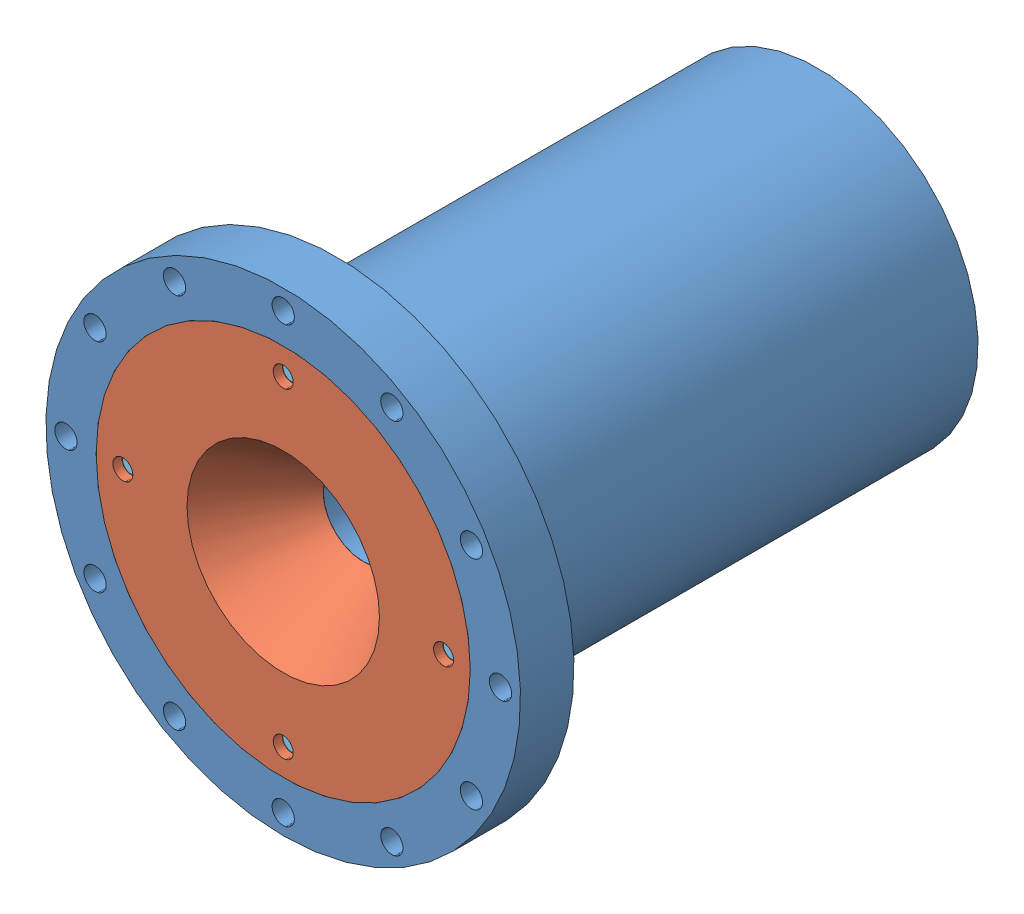
SolidWorks assembly ModularNozzeAssy, configuration Default. Lengths in mm.
Overall size (112.78 112.78 127).
11 component instances, 5 part files, 22 mates.
Components (placement in the parent):
- ModularNozzleBase-1: ModularNozzleBase [Default] at origin size (112.78 112.78 127)
- ConvergingInsert1-1: ConvergingInsert1 [Default] at (0 0 63.5) size (88.9 88.9 19.05)
- DivergingInsert1-1: DivergingInsert1 [Default] at (0 0 38.1) size (63.5 63.5 101.6)
- socket head cap screw_ai-2: socket head cap screw_ai [HX-SHCS 0.19-32x2x1.125-N] at (-22.86 0 44.45) x (0 0 -1) z (0.412891 -0.91078 0) size (55.63 7.94 7.94)
- socket head cap screw_ai-3: socket head cap screw_ai [HX-SHCS 0.19-32x2x1.125-N] at (0 22.86 44.45) x (0 0 -1) z (0.931686 -0.363265 0) size (55.63 7.94 7.94)
- socket head cap screw_ai-4: socket head cap screw_ai [HX-SHCS 0.19-32x2x1.125-N] at (22.86 0 44.45) x (0 0 -1) z (0.730359 0.683064 0) size (55.63 7.94 7.94)
- socket head cap screw_ai-5: socket head cap screw_ai [HX-SHCS 0.19-32x2x1.125-N] at (0 -22.86 44.45) x (0 0 -1) z (0.252159 -0.967686 0) size (55.63 7.94 7.94)
- dowel pin (hardened production)_ai-3: dowel pin (hardened production)_ai [ASME B18.8.2 - 0.1877x0.375] at (0 38.1 61.595) x (0 0 -1) z (0.976041 0.217586 0) size (9.53 4.77 4.77)
- dowel pin (hardened production)_ai-4: dowel pin (hardened production)_ai [ASME B18.8.2 - 0.1877x0.375] at (-38.1 0 61.595) x (0 0 -1) z (1 0 0) size (9.53 4.77 4.77)
- dowel pin (hardened production)_ai-5: dowel pin (hardened production)_ai [ASME B18.8.2 - 0.1877x0.375] at (38.1 0 61.595) x (0 0 -1) z (0.837341 0.546681 0) size (9.53 4.77 4.77)
- dowel pin (hardened production)_ai-6: dowel pin (hardened production)_ai [ASME B18.8.2 - 0.1877x0.375] at (0 -38.1 61.595) x (0 0 -1) z (1 0 0) size (9.53 4.77 4.77)
Mates (geometry in assembly coordinates):
- Concentric1: concentric: cylinder of ModularNozzleBase-1 through (0 0 58.42) axis (0 0 1) radius 44.45; cylinder of ConvergingInsert1-1 through (0 0 81.9542) axis (0 0 1) radius 44.45
- Concentric2: concentric: cylinder of ModularNozzleBase-1 through (0 38.1 58.42) axis (0 0 1) radius 2.3813; cylinder of ConvergingInsert1-1 through (0 38.1 63.5) axis (0 0 1) radius 2.3813
- Concentric3: concentric: cylinder of ModularNozzleBase-1 through (0 0 38.1) axis (0 0 -1) radius 31.75; cylinder of DivergingInsert1-1 through (0 0 99.0332) axis (0 0 1) radius 31.75
- Concentric4: concentric: cylinder of ModularNozzleBase-1 through (-22.86 0 44.45) axis (0 0 1) radius 2.5527; cylinder of DivergingInsert1-1 through (-22.86 0 38.1) axis (0 0 1) radius 2.0193
- Coincident1: coincident: plane of ModularNozzleBase-1 through (0 0 38.1) normal (0 0 -1); plane of DivergingInsert1-1 through (0 31.75 38.1) normal (0 0 1)
- Concentric5: concentric: cylinder of DivergingInsert1-1 through (-22.86 0 38.1) axis (0 0 1) radius 2.0193; cylinder of socket head cap screw_ai-2 through (-22.86 0 76.2) axis (0 0 1) radius 3.9688
- Concentric6: concentric: cylinder of DivergingInsert1-1 through (0 22.86 38.1) axis (0 0 1) radius 2.0193; cylinder of socket head cap screw_ai-3 through (0 22.86 76.2) axis (0 0 1) radius 3.9688
- Concentric7: concentric: cylinder of ModularNozzleBase-1 through (22.86 0 44.45) axis (0 0 1) radius 2.5527; cylinder of socket head cap screw_ai-4 through (22.86 0 76.2) axis (0 0 1) radius 3.9688
- Concentric8: concentric: cylinder of DivergingInsert1-1 through (0 -22.86 38.1) axis (0 0 1) radius 2.0193; cylinder of socket head cap screw_ai-5 through (0 -22.86 76.2) axis (0 0 1) radius 3.9688
- Concentric9: concentric: cylinder of ModularNozzleBase-1 through (0 38.1 58.42) axis (0 0 1) radius 2.3813; cylinder of dowel pin (hardened production)_ai-3 through (0 38.1 67.945) axis (0 0 1) radius 2.3838
- Concentric10: concentric: cylinder of ModularNozzleBase-1 through (-38.1 0 58.42) axis (0 0 1) radius 2.3813; cylinder of dowel pin (hardened production)_ai-4 through (-38.1 0 67.945) axis (0 0 1) radius 2.3838
- Concentric11: concentric: cylinder of ModularNozzleBase-1 through (38.1 0 58.42) axis (0 0 1) radius 2.3813; cylinder of dowel pin (hardened production)_ai-5 through (38.1 0 67.945) axis (0 0 1) radius 2.3838
- Concentric12: concentric: cylinder of ModularNozzleBase-1 through (0 -38.1 58.42) axis (0 0 1) radius 2.3813; cylinder of dowel pin (hardened production)_ai-6 through (0 -38.1 67.945) axis (0 0 1) radius 2.3838
- Coincident6: coincident: circle of ModularNozzleBase-1; plane of dowel pin (hardened production)_ai-5 through (38.1 0 52.07) normal (0 0 -1)
- Coincident7: coincident: plane of dowel pin (hardened production)_ai-3 through (-0.4081 39.9308 61.595) normal (0 0 1); plane of dowel pin (hardened production)_ai-5 through (37.0745 1.5707 61.595) normal (0 0 1)
- Coincident8: coincident: plane of dowel pin (hardened production)_ai-3 through (-0.4081 39.9308 61.595) normal (0 0 1); plane of dowel pin (hardened production)_ai-4 through (-38.1 1.8758 61.595) normal (0 0 1)
- Coincident9: coincident: plane of dowel pin (hardened production)_ai-4 through (-38.1 1.8758 61.595) normal (0 0 1); plane of dowel pin (hardened production)_ai-6 through (0 -36.2242 61.595) normal (0 0 1)
- Coincident10: coincident: plane of ModularNozzleBase-1 through (0 0 44.45) normal (0 0 1); plane of ConvergingInsert1-1 through (0 9.525 44.45) normal (0 0 -1)
- Coincident11: coincident: plane of ModularNozzleBase-1 through (-20.3073 0 39.624) normal (0 0 1); plane of socket head cap screw_ai-2 through (-19.2453 1.6387 39.624) normal (0 0 -1)
- Coincident12: coincident: plane of socket head cap screw_ai-2 through (-22.86 0 44.45) normal (0 0 1); plane of socket head cap screw_ai-5 through (0 -22.86 44.45) normal (0 0 1)
- Coincident13: coincident: plane of socket head cap screw_ai-4 through (22.86 0 44.45) normal (0 0 1); plane of socket head cap screw_ai-5 through (0 -22.86 44.45) normal (0 0 1)
- Coincident14: coincident: plane of socket head cap screw_ai-3 through (0 22.86 44.45) normal (0 0 1); plane of socket head cap screw_ai-4 through (22.86 0 44.45) normal (0 0 1)
